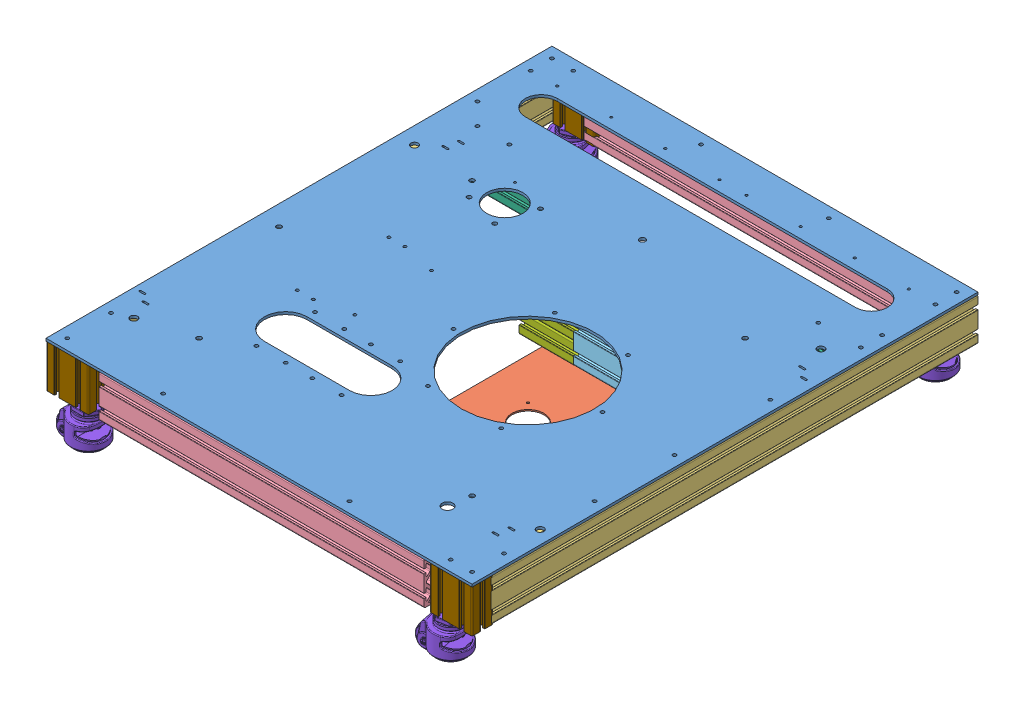
SolidWorks assembly T-slot_base, configuration Default. Lengths in mm.
Overall size (801.63 156.26 997.79).
24 component instances, 9 part files, 64 mates.
Components (placement in the parent):
- Aluminum_plate-1: Aluminum_plate [Default] at (380 20 20) size (800 4.83 950)
- Sample Turntable Motor Mount-1: Sample Turntable Motor Mount [Default] at (496.5096 -59.756 13.6218) x (0 0 -1) z (-1 0 0) size (355 2.54 220)
- 5537T715_ALUMINUM T-SLOTTED FRAMING EXTRUSION-1: 5537T715_ALUMINUM T-SLOTTED FRAMING EXTRUSION [5537T715] at (-0.061 -19.878 -72.8) x (0 1 0) z (0 0 1) size (79.76 39.88 914.4)
- 5537T715_ALUMINUM T-SLOTTED FRAMING EXTRUSION-2: 5537T715_ALUMINUM T-SLOTTED FRAMING EXTRUSION [5537T715] at (760.061 -19.878 -72.8) x (0 1 0) z (0 0 1) size (79.76 39.88 914.4)
- 5537T108_ALUMINUM T-SLOTTED FRAMING EXTRUSION-1: 5537T108_ALUMINUM T-SLOTTED FRAMING EXTRUSION [5537T108] at (384.678 -19.878 400.061) x (0 1 0) z (-1 0 0) size (79.76 39.88 609.6)
- 5537T108_ALUMINUM T-SLOTTED FRAMING EXTRUSION-2: 5537T108_ALUMINUM T-SLOTTED FRAMING EXTRUSION [5537T108] at (384.678 -19.878 -510.061) x (0 1 0) z (1 0 0) size (79.76 39.88 609.6)
- 5537T714_ALUMINUM T-SLOTTED FRAMING EXTRUSION-1: 5537T714_ALUMINUM T-SLOTTED FRAMING EXTRUSION [5537T714] at (587.722 -19.878 180.061) x (0 -1 0) z (-1 0 0) size (79.76 39.88 304.8)
- 5537T714_ALUMINUM T-SLOTTED FRAMING EXTRUSION-2: 5537T714_ALUMINUM T-SLOTTED FRAMING EXTRUSION [5537T714] at (587.722 -19.878 -134.939) x (0 -1 0) z (-1 0 0) size (79.76 39.88 304.8)
- 5537T711_ALUMINUM T-SLOTTED FRAMING 6in-3: 5537T711_ALUMINUM T-SLOTTED FRAMING 6in [5537T711] at (-205.722 0 -330) x (0 0 -1) z (1 0 0) size (40 40 154.4)
- 5537T711_ALUMINUM T-SLOTTED FRAMING 6in-4: 5537T711_ALUMINUM T-SLOTTED FRAMING 6in [5537T711] at (-205.722 -40 -330) x (0 0 -1) z (1 0 0) size (40 40 154.4)
- 5537T711_ALUMINUM T-SLOTTED FRAMING 6in-6: 5537T711_ALUMINUM T-SLOTTED FRAMING 6in [5537T711] at (965.722 0 -330) x (0 0 1) z (-1 0 0) size (40 40 154.4)
- 5537T711_ALUMINUM T-SLOTTED FRAMING 6in-9: 5537T711_ALUMINUM T-SLOTTED FRAMING 6in [5537T711] at (965.722 -40 -330) x (0 0 1) z (-1 0 0) size (40 40 154.4)
- 5537T711_ALUMINUM T-SLOTTED FRAMING 4in-1: 5537T711_ALUMINUM T-SLOTTED FRAMING 4in [5537T711] at (713.722 0 -134.878) x (0 0 -1) z (-1 0 0) size (40 40 101.6)
- 5537T711_ALUMINUM T-SLOTTED FRAMING 4in-2: 5537T711_ALUMINUM T-SLOTTED FRAMING 4in [5537T711] at (713.722 -40 -134.878) x (0 0 -1) z (-1 0 0) size (40 40 101.6)
- 5537T711_ALUMINUM T-SLOTTED FRAMING 6in-11: 5537T711_ALUMINUM T-SLOTTED FRAMING 6in [5537T711] at (-205.722 0 20) x (0 0 1) z (1 0 0) size (40 40 154.4)
- 5537T711_ALUMINUM T-SLOTTED FRAMING 6in-15: 5537T711_ALUMINUM T-SLOTTED FRAMING 6in [5537T711] at (399.878 -40 20) x (0 0 1) z (-1 0 0) size (40 40 154.4)
- 2445T430_LEVELING THREADED-STEM CASTER-1: 2445T430_LEVELING THREADED-STEM CASTER [2445T43] at (39.817 -109.2125 400.061) size (85.56 90.91 65.55)
- 5537T714_ALUMINUM T-SLOTTED FRAMING EXTRUSION 40mm-1: 5537T714_ALUMINUM T-SLOTTED FRAMING EXTRUSION 40mm [5537T714] at (19.878 -132.4 400.061) x (1 0 0) z (0 1 0) size (79.76 39.88 80)
- 5537T714_ALUMINUM T-SLOTTED FRAMING EXTRUSION 40mm-2: 5537T714_ALUMINUM T-SLOTTED FRAMING EXTRUSION 40mm [5537T714] at (740.122 92.4 400.061) x (-1 0 0) z (0 -1 0) size (79.76 39.88 80)
- 5537T714_ALUMINUM T-SLOTTED FRAMING EXTRUSION 40mm-3: 5537T714_ALUMINUM T-SLOTTED FRAMING EXTRUSION 40mm [5537T714] at (59.756 92.4 -510.061) x (-1 0 0) z (0 -1 0) size (79.76 39.88 80)
- 5537T714_ALUMINUM T-SLOTTED FRAMING EXTRUSION 40mm-4: 5537T714_ALUMINUM T-SLOTTED FRAMING EXTRUSION 40mm [5537T714] at (700.244 -132.4 -510.061) x (1 0 0) z (0 1 0) size (79.76 39.88 80)
- 2445T430_LEVELING THREADED-STEM CASTER-2: 2445T430_LEVELING THREADED-STEM CASTER [2445T43] at (720.183 -109.2125 400.061) x (0.982082 0 -0.188455) z (0.188455 0 0.982082) size (85.56 90.91 65.55)
- 2445T430_LEVELING THREADED-STEM CASTER-4: 2445T430_LEVELING THREADED-STEM CASTER [2445T43] at (39.817 -109.2125 -510.061) x (0.918365 0 -0.395734) z (0.395734 0 0.918365) size (85.56 90.91 65.55)
- 2445T430_LEVELING THREADED-STEM CASTER-7: 2445T430_LEVELING THREADED-STEM CASTER [2445T43] at (720.183 -109.2125 -510.061) x (0.827332 0 -0.561714) z (0.561714 0 0.827332) size (85.56 90.91 65.55)
Mates (geometry in assembly coordinates):
- Coincident39: coincident anti-aligned: plane of Aluminum_plate-1 through (380 20 20) normal (0 -1 0); plane of 5537T715_ALUMINUM T-SLOTTED FRAMING EXTRUSION-1 through (-16.952 20 384.4) normal (0 1 0)
- Coincident40: coincident aligned: plane of Aluminum_plate-1 through (380 20 -530) normal (0 0 -1); plane of 5537T715_ALUMINUM T-SLOTTED FRAMING EXTRUSION-1 through (-10.7544 -42.8916 -530) normal (0 0 -1)
- Coincident41: coincident aligned: plane of Aluminum_plate-1 through (-20 24.826 420) normal (-1 0 0); plane of 5537T715_ALUMINUM T-SLOTTED FRAMING EXTRUSION-1 through (-20 -4.7015 384.4) normal (-1 0 0)
- Coincident42: coincident anti-aligned: plane of Aluminum_plate-1 through (380 20 20) normal (0 -1 0); plane of 5537T715_ALUMINUM T-SLOTTED FRAMING EXTRUSION-2 through (743.17 20 384.4) normal (0 1 0)
- Coincident43: coincident aligned: plane of Aluminum_plate-1 through (380 20 -530) normal (0 0 -1); plane of 5537T715_ALUMINUM T-SLOTTED FRAMING EXTRUSION-2 through (749.3676 -42.8916 -530) normal (0 0 -1)
- Coincident44: coincident aligned: plane of Aluminum_plate-1 through (780 24.826 420) normal (1 0 0); plane of 5537T715_ALUMINUM T-SLOTTED FRAMING EXTRUSION-2 through (780 -4.7015 384.4) normal (1 0 0)
- Coincident47: coincident anti-aligned: plane of Aluminum_plate-1 through (380 20 20) normal (0 -1 0); plane of 5537T108_ALUMINUM T-SLOTTED FRAMING EXTRUSION-1 through (79.878 20 383.17) normal (0 1 0)
- Coincident48: coincident aligned: plane of Aluminum_plate-1 through (-20 24.826 420) normal (0 0 1); plane of 5537T108_ALUMINUM T-SLOTTED FRAMING EXTRUSION-1 through (79.878 16.952 420) normal (0 0 1)
- Distance4: distance = 60 mm anti-aligned: plane of 5537T715_ALUMINUM T-SLOTTED FRAMING EXTRUSION-1 through (19.878 -4.7015 384.4) normal (1 0 0); plane of 5537T108_ALUMINUM T-SLOTTED FRAMING EXTRUSION-1 through (79.878 -42.8916 389.3676) normal (-1 0 0)
- Coincident50: coincident anti-aligned: plane of Aluminum_plate-1 through (380 20 20) normal (0 -1 0); plane of 5537T108_ALUMINUM T-SLOTTED FRAMING EXTRUSION-2 through (689.478 20 -493.17) normal (0 1 0)
- Distance6: distance = 60 mm anti-aligned: plane of 5537T108_ALUMINUM T-SLOTTED FRAMING EXTRUSION-2 through (79.878 -42.8916 -499.3676) normal (-1 0 0); plane of 5537T715_ALUMINUM T-SLOTTED FRAMING EXTRUSION-1 through (19.878 -4.7015 384.4) normal (1 0 0)
- Coincident53: coincident aligned: plane of Aluminum_plate-1 through (380 20 -530) normal (0 0 -1); plane of 5537T108_ALUMINUM T-SLOTTED FRAMING EXTRUSION-2 through (689.478 16.952 -530) normal (0 0 -1)
- Coincident56: coincident anti-aligned: plane of Aluminum_plate-1 through (380 20 20) normal (0 -1 0); plane of 5537T714_ALUMINUM T-SLOTTED FRAMING EXTRUSION-1 through (435.322 20 196.952) normal (0 1 0)
- Coincident58: coincident anti-aligned: plane of 5537T715_ALUMINUM T-SLOTTED FRAMING EXTRUSION-2 through (740.122 -4.7015 384.4) normal (-1 0 0); plane of 5537T714_ALUMINUM T-SLOTTED FRAMING EXTRUSION-1 through (740.122 3.1356 190.7544) normal (1 0 0)
- Distance7: distance = 220 mm aligned: plane of Aluminum_plate-1 through (-20 24.826 420) normal (0 0 1); plane of 5537T714_ALUMINUM T-SLOTTED FRAMING EXTRUSION-1 through (435.322 -35.0545 200) normal (0 0 1)
- Coincident61: coincident anti-aligned: plane of Aluminum_plate-1 through (380 20 20) normal (0 -1 0); plane of 5537T714_ALUMINUM T-SLOTTED FRAMING EXTRUSION-2 through (435.322 20 -118.048) normal (0 1 0)
- Coincident62: coincident anti-aligned: plane of 5537T715_ALUMINUM T-SLOTTED FRAMING EXTRUSION-2 through (740.122 -4.7015 384.4) normal (-1 0 0); plane of 5537T714_ALUMINUM T-SLOTTED FRAMING EXTRUSION-2 through (740.122 3.1356 -124.2456) normal (1 0 0)
- Distance9: distance = 535 mm aligned: plane of Aluminum_plate-1 through (-20 24.826 420) normal (0 0 1); plane of 5537T714_ALUMINUM T-SLOTTED FRAMING EXTRUSION-2 through (435.322 -35.0545 -115) normal (0 0 1)
- Coincident66: coincident anti-aligned: plane of Aluminum_plate-1 through (380 20 20) normal (0 -1 0); plane of 5537T711_ALUMINUM T-SLOTTED FRAMING 6in-3 through (174.278 20 -313.048) normal (0 1 0)
- Coincident67: coincident anti-aligned: plane of 5537T715_ALUMINUM T-SLOTTED FRAMING EXTRUSION-1 through (19.878 -4.7015 384.4) normal (1 0 0); plane of 5537T711_ALUMINUM T-SLOTTED FRAMING 6in-3 through (19.878 20 -395) normal (-1 0 0)
- Distance10: distance = 180 mm aligned: plane of 5537T711_ALUMINUM T-SLOTTED FRAMING 6in-3 through (174.278 -16.952 -350) normal (0 0 -1); plane of Aluminum_plate-1 through (380 20 -530) normal (0 0 -1)
- Coincident69: coincident anti-aligned: plane of 5537T711_ALUMINUM T-SLOTTED FRAMING 6in-3 through (174.278 -20 -346.952) normal (0 -1 0); plane of 5537T711_ALUMINUM T-SLOTTED FRAMING 6in-4 through (174.278 -20 -313.048) normal (0 1 0)
- Coincident70: coincident anti-aligned: plane of 5537T715_ALUMINUM T-SLOTTED FRAMING EXTRUSION-1 through (19.878 -4.7015 384.4) normal (1 0 0); plane of 5537T711_ALUMINUM T-SLOTTED FRAMING 6in-4 through (19.878 -20 -395) normal (-1 0 0)
- Distance11: distance = 180 mm aligned: plane of 5537T711_ALUMINUM T-SLOTTED FRAMING 6in-4 through (174.278 -56.952 -350) normal (0 0 -1); plane of Aluminum_plate-1 through (380 20 -530) normal (0 0 -1)
- Coincident72: coincident anti-aligned: plane of Aluminum_plate-1 through (380 20 20) normal (0 -1 0); plane of 5537T711_ALUMINUM T-SLOTTED FRAMING 6in-6 through (585.722 20 -346.952) normal (0 1 0)
- Coincident73: coincident anti-aligned: plane of 5537T715_ALUMINUM T-SLOTTED FRAMING EXTRUSION-2 through (740.122 -4.7015 384.4) normal (-1 0 0); plane of 5537T711_ALUMINUM T-SLOTTED FRAMING 6in-6 through (740.122 20 -265) normal (1 0 0)
- Distance13: distance = 180 mm aligned: plane of Aluminum_plate-1 through (380 20 -530) normal (0 0 -1); plane of 5537T711_ALUMINUM T-SLOTTED FRAMING 6in-6 through (585.722 -16.952 -350) normal (0 0 -1)
- Coincident85: coincident anti-aligned: plane of 5537T711_ALUMINUM T-SLOTTED FRAMING 6in-6 through (585.722 -20 -346.952) normal (0 -1 0); plane of 5537T711_ALUMINUM T-SLOTTED FRAMING 6in-9 through (585.722 -20 -346.952) normal (0 1 0)
- Coincident86: coincident anti-aligned: plane of 5537T715_ALUMINUM T-SLOTTED FRAMING EXTRUSION-2 through (740.122 -4.7015 384.4) normal (-1 0 0); plane of 5537T711_ALUMINUM T-SLOTTED FRAMING 6in-9 through (740.122 -20 -265) normal (1 0 0)
- Distance14: distance = 180 mm aligned: plane of Aluminum_plate-1 through (380 20 -530) normal (0 0 -1); plane of 5537T711_ALUMINUM T-SLOTTED FRAMING 6in-9 through (585.722 -56.952 -350) normal (0 0 -1)
- Coincident94: coincident anti-aligned: plane of Aluminum_plate-1 through (380 20 20) normal (0 -1 0); plane of 5537T711_ALUMINUM T-SLOTTED FRAMING 4in-1 through (333.722 20 -117.926) normal (0 1 0)
- Coincident95: coincident anti-aligned: plane of 5537T714_ALUMINUM T-SLOTTED FRAMING EXTRUSION-2 through (435.322 3.1356 -124.2456) normal (-1 0 0); plane of 5537T711_ALUMINUM T-SLOTTED FRAMING 4in-1 through (435.322 -20 -164.878) normal (1 0 0)
- Coincident96: coincident aligned: plane of 5537T714_ALUMINUM T-SLOTTED FRAMING EXTRUSION-2 through (435.322 16.952 -154.878) normal (0 0 -1); plane of 5537T711_ALUMINUM T-SLOTTED FRAMING 4in-1 through (333.722 16.952 -154.878) normal (0 0 -1)
- Coincident97: coincident anti-aligned: plane of 5537T711_ALUMINUM T-SLOTTED FRAMING 4in-1 through (333.722 -20 -151.83) normal (0 -1 0); plane of 5537T711_ALUMINUM T-SLOTTED FRAMING 4in-2 through (333.722 -20 -117.926) normal (0 1 0)
- Coincident98: coincident anti-aligned: plane of 5537T714_ALUMINUM T-SLOTTED FRAMING EXTRUSION-2 through (435.322 3.1356 -124.2456) normal (-1 0 0); plane of 5537T711_ALUMINUM T-SLOTTED FRAMING 4in-2 through (435.322 -60 -164.878) normal (1 0 0)
- Coincident99: coincident aligned: plane of 5537T714_ALUMINUM T-SLOTTED FRAMING EXTRUSION-2 through (435.322 16.952 -154.878) normal (0 0 -1); plane of 5537T711_ALUMINUM T-SLOTTED FRAMING 4in-2 through (333.722 -23.048 -154.878) normal (0 0 -1)
- Coincident102: coincident aligned: plane of 5537T711_ALUMINUM T-SLOTTED FRAMING 6in-3 through (174.278 -20 -346.952) normal (0 -1 0); plane of 5537T711_ALUMINUM T-SLOTTED FRAMING 6in-11 through (174.278 -20 3.048) normal (0 -1 0)
- Coincident103: coincident anti-aligned: plane of 5537T715_ALUMINUM T-SLOTTED FRAMING EXTRUSION-1 through (19.878 -4.7015 384.4) normal (1 0 0); plane of 5537T711_ALUMINUM T-SLOTTED FRAMING 6in-11 through (19.878 -20 85) normal (-1 0 0)
- Distance20: distance = 570 mm anti-aligned: plane of 5537T711_ALUMINUM T-SLOTTED FRAMING 6in-11 through (174.278 16.952 40) normal (0 0 1); plane of Aluminum_plate-1 through (380 20 -530) normal (0 0 -1)
- Coincident110: coincident anti-aligned: plane of 5537T711_ALUMINUM T-SLOTTED FRAMING 6in-11 through (174.278 -20 3.048) normal (0 -1 0); plane of 5537T711_ALUMINUM T-SLOTTED FRAMING 6in-15 through (19.878 -20 3.048) normal (0 1 0)
- Coincident111: coincident anti-aligned: plane of 5537T715_ALUMINUM T-SLOTTED FRAMING EXTRUSION-1 through (19.878 -4.7015 384.4) normal (1 0 0); plane of 5537T711_ALUMINUM T-SLOTTED FRAMING 6in-15 through (19.878 -29.2456 16.9254) normal (-1 0 0)
- Coincident112: coincident aligned: plane of 5537T711_ALUMINUM T-SLOTTED FRAMING 6in-11 through (174.278 -16.952 0) normal (0 0 -1); plane of 5537T711_ALUMINUM T-SLOTTED FRAMING 6in-15 through (19.878 -23.048 0) normal (0 0 -1)
- Coincident117: coincident anti-aligned: plane of Sample Turntable Motor Mount-1 through (496.5096 -59.756 13.6218) normal (0 1 0); plane of 5537T714_ALUMINUM T-SLOTTED FRAMING EXTRUSION-1 through (435.322 -59.756 163.17) normal (0 -1 0)
- Concentric3: concentric aligned: circle of Aluminum_plate-1; circle of Sample Turntable Motor Mount-1
- Coincident118: coincident anti-aligned: plane of Aluminum_plate-1 through (380 20 20) normal (0 -1 0); plane of 5537T714_ALUMINUM T-SLOTTED FRAMING EXTRUSION 40mm-1 through (-3.1356 20 389.3676) normal (0 1 0)
- Coincident119: coincident: line of Aluminum_plate-1 through (-20 20 -530) axis (0 0 1); plane of 5537T714_ALUMINUM T-SLOTTED FRAMING EXTRUSION 40mm-1 through (-20 20 416.952) normal (-1 0 0)
- Coincident120: coincident aligned: plane of Aluminum_plate-1 through (-20 24.826 420) normal (0 0 1); plane of 5537T714_ALUMINUM T-SLOTTED FRAMING EXTRUSION 40mm-1 through (-16.952 20 420) normal (0 0 1)
- Coincident121: coincident anti-aligned: plane of Aluminum_plate-1 through (380 20 20) normal (0 -1 0); plane of 5537T714_ALUMINUM T-SLOTTED FRAMING EXTRUSION 40mm-2 through (700.122 20 380.122) normal (0 1 0)
- Coincident122: coincident aligned: plane of Aluminum_plate-1 through (-20 24.826 420) normal (0 0 1); plane of 5537T714_ALUMINUM T-SLOTTED FRAMING EXTRUSION 40mm-2 through (776.952 -60 420) normal (0 0 1)
- Coincident123: coincident aligned: plane of Aluminum_plate-1 through (780 24.826 420) normal (1 0 0); plane of 5537T714_ALUMINUM T-SLOTTED FRAMING EXTRUSION 40mm-2 through (780 -60 416.952) normal (1 0 0)
- Coincident124: coincident anti-aligned: plane of Aluminum_plate-1 through (380 20 20) normal (0 -1 0); plane of 5537T714_ALUMINUM T-SLOTTED FRAMING EXTRUSION 40mm-3 through (19.756 20 -530) normal (0 1 0)
- Coincident125: coincident aligned: plane of Aluminum_plate-1 through (380 20 -530) normal (0 0 -1); plane of 5537T714_ALUMINUM T-SLOTTED FRAMING EXTRUSION 40mm-3 through (44.5795 -60 -530) normal (0 0 -1)
- Coincident126: coincident anti-aligned: plane of 5537T715_ALUMINUM T-SLOTTED FRAMING EXTRUSION-1 through (19.878 -4.7015 384.4) normal (1 0 0); plane of 5537T714_ALUMINUM T-SLOTTED FRAMING EXTRUSION 40mm-3 through (19.878 -60 -526.952) normal (-1 0 0)
- Coincident127: coincident anti-aligned: plane of Aluminum_plate-1 through (380 20 20) normal (0 -1 0); plane of 5537T714_ALUMINUM T-SLOTTED FRAMING EXTRUSION 40mm-4 through (677.2304 20 -520.7544) normal (0 1 0)
- Coincident128: coincident aligned: plane of Aluminum_plate-1 through (380 20 -530) normal (0 0 -1); plane of 5537T714_ALUMINUM T-SLOTTED FRAMING EXTRUSION 40mm-4 through (715.4205 20 -530) normal (0 0 -1)
- Coincident129: coincident anti-aligned: plane of 5537T715_ALUMINUM T-SLOTTED FRAMING EXTRUSION-2 through (740.122 -56.708 384.4) normal (-1 0 0); plane of 5537T714_ALUMINUM T-SLOTTED FRAMING EXTRUSION 40mm-4 through (740.122 20 -526.952) normal (1 0 0)
- Coincident130: coincident anti-aligned: plane of 2445T430_LEVELING THREADED-STEM CASTER-1 through (15.8754 -60 400.061) normal (0 1 0); plane of 5537T714_ALUMINUM T-SLOTTED FRAMING EXTRUSION 40mm-1 through (59.878 -60 380.122) normal (0 -1 0)
- Concentric5: concentric aligned: circle of 5537T714_ALUMINUM T-SLOTTED FRAMING EXTRUSION 40mm-1; circle of 2445T430_LEVELING THREADED-STEM CASTER-1
- Coincident131: coincident anti-aligned: plane of 5537T714_ALUMINUM T-SLOTTED FRAMING EXTRUSION 40mm-2 through (763.1356 -60 389.3676) normal (0 -1 0); plane of 2445T430_LEVELING THREADED-STEM CASTER-2 through (696.6704 -60 404.5729) normal (0 1 0)
- Concentric6: concentric anti-aligned: circle of 2445T430_LEVELING THREADED-STEM CASTER-2; circle of 5537T714_ALUMINUM T-SLOTTED FRAMING EXTRUSION 40mm-2
- Coincident132: coincident anti-aligned: plane of 5537T714_ALUMINUM T-SLOTTED FRAMING EXTRUSION 40mm-3 through (82.7696 -60 -520.7544) normal (0 -1 0); plane of 2445T430_LEVELING THREADED-STEM CASTER-4 through (17.8299 -60 -500.5865) normal (0 1 0)
- Concentric7: concentric anti-aligned: circle of 5537T714_ALUMINUM T-SLOTTED FRAMING EXTRUSION 40mm-3; circle of 2445T430_LEVELING THREADED-STEM CASTER-4
- Coincident134: coincident anti-aligned: plane of 5537T714_ALUMINUM T-SLOTTED FRAMING EXTRUSION 40mm-4 through (740.244 -60 -530) normal (0 -1 0); plane of 2445T430_LEVELING THREADED-STEM CASTER-7 through (700.3754 -60 -496.6127) normal (0 1 0)
- Concentric9: concentric anti-aligned: circle of 5537T714_ALUMINUM T-SLOTTED FRAMING EXTRUSION 40mm-4; circle of 2445T430_LEVELING THREADED-STEM CASTER-7
